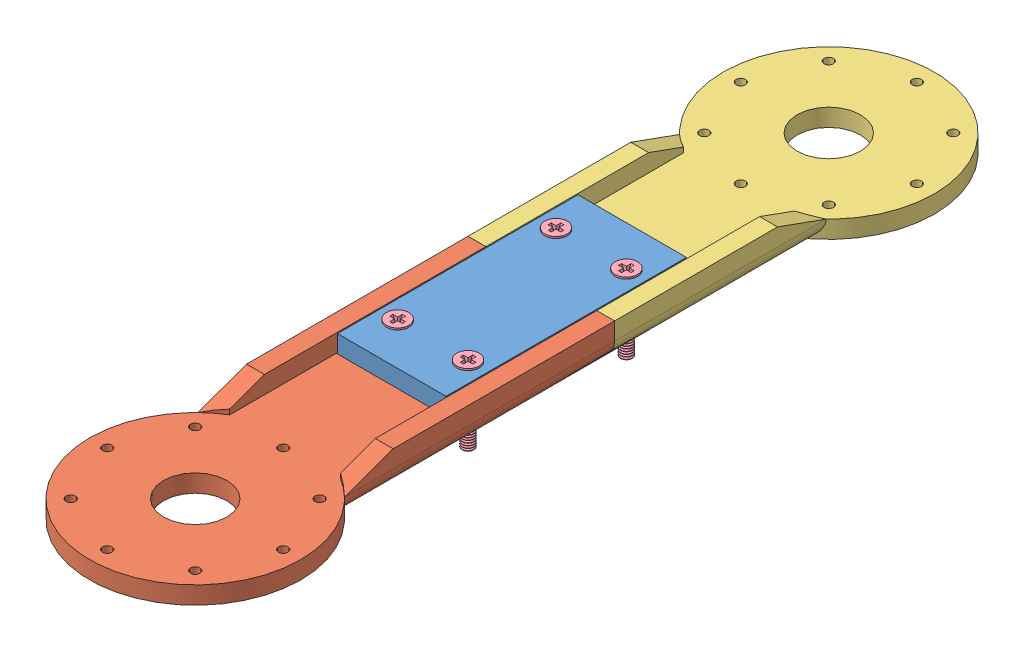
SolidWorks assembly Ensamblaje-Eslabon2AB, configuration Predeterminado. Lengths in mm.
Overall size (35.99 13 144).
7 component instances, 4 part files, 14 mates.
Components (placement in the parent):
- Agarre-Eslabon2AyB-1: Agarre-Eslabon2AyB [Predeterminado] at (-14.421 1.0451 41) size (18.5 3 41)
- Eslabon2A-1: Eslabon2A [Predeterminado] at (-11.6524 -1.9549 75.4017) x (1 0 0) z (0 0 1) size (35.99 6 77)
- Eslabon2B-1: Eslabon2B [Predeterminado] at (-11.1985 -1.9549 7.7213) x (-1 0 0) z (0 0 -1) size (35.99 6 77)
- flat head screw_am-2: flat head screw_am [B18.6.7M - M2 x 0.4 x 13 Type I Cross Recessed FHMS --13S] at (-5.4254 4.3451 55.0617) x (0 -1 0) z (0.013375 0 0.999911) size (13 3.8 3.8)
- flat head screw_am-3: flat head screw_am [B18.6.7M - M2 x 0.4 x 13 Type I Cross Recessed FHMS --13S] at (-17.425 4.3451 55.0617) x (0 -1 0) z (0 0 1) size (13 3.8 3.8)
- flat head screw_am-4: flat head screw_am [B18.6.7M - M2 x 0.4 x 13 Type I Cross Recessed FHMS --13S] at (-17.4254 4.3451 28.0617) x (0 -1 0) z (0 0 1) size (13 3.8 3.8)
- flat head screw_am-5: flat head screw_am [B18.6.7M - M2 x 0.4 x 13 Type I Cross Recessed FHMS --13S] at (-5.4254 4.3451 28.0617) x (0 -1 0) z (0 0 1) size (13 3.8 3.8)
Mates (geometry in assembly coordinates):
- Coincidente2: coincident: plane of Eslabon2A-1 through (1.0746 1.0451 36.5614) normal (1 0 0); plane of Eslabon2B-1 through (1.0746 1.0451 36.5614) normal (1 0 0)
- Coincidente3: coincident: plane of Eslabon2A-1 through (-18.9254 1.0451 46.5614) normal (0 0 -1); plane of Eslabon2B-1 through (-3.9254 1.0451 46.5614) normal (0 0 1)
- Coincidente4: coincident: plane of Eslabon2A-1 through (-11.4254 1.0451 95.565) normal (0 1 0); plane of Eslabon2B-1 through (-11.4254 1.0451 -12.4419) normal (0 1 0)
- Coincidente5: coincident: plane of Agarre-Eslabon2AyB-1 through (-14.421 1.0451 41) normal (0 -1 0); plane of Eslabon2A-1 through (-11.4254 1.0451 95.565) normal (0 1 0)
- Concéntrica1: concentric: cylinder of Agarre-Eslabon2AyB-1 through (-5.4254 4.0451 55.0617) axis (0 -1 0) radius 1; cylinder of Eslabon2A-1 through (-5.4254 1.0451 55.0614) axis (0 -1 0) radius 1
- Concéntrica2: concentric: cylinder of Agarre-Eslabon2AyB-1 through (-5.4254 4.0451 28.0617) axis (0 -1 0) radius 1; cylinder of Eslabon2B-1 through (-5.4254 1.0451 28.0617) axis (0 -1 0) radius 1
- Concéntrica3: concentric: cylinder of Agarre-Eslabon2AyB-1 through (-5.4254 4.0451 55.0617) axis (0 -1 0) radius 1; cone of flat head screw_am-2 through (-5.4254 4.0451 55.0617) axis (0 -1 0)
- Concéntrica4: concentric: cylinder of Agarre-Eslabon2AyB-1 through (-17.425 4.0451 55.0617) axis (0 -1 0) radius 0.9998; cone of flat head screw_am-3 through (-17.425 4.0451 55.0617) axis (0 -1 0)
- Concéntrica5: concentric: cylinder of Agarre-Eslabon2AyB-1 through (-17.4254 4.0451 28.0617) axis (0 -1 0) radius 1; cone of flat head screw_am-4 through (-17.4254 4.0451 28.0617) axis (0 -1 0)
- Concéntrica6: concentric: cylinder of Agarre-Eslabon2AyB-1 through (-5.4254 4.0451 28.0617) axis (0 -1 0) radius 1; cone of flat head screw_am-5 through (-5.4254 4.0451 28.0617) axis (0 -1 0)
- Coincidente6: coincident: plane of flat head screw_am-4 through (-17.4254 4.3451 28.0617) normal (0 1 0); plane of flat head screw_am-5 through (-5.4254 4.3451 28.0617) normal (0 1 0)
- Coincidente7: coincident: circle of flat head screw_am-2; plane of flat head screw_am-5 through (-5.4254 4.3451 28.0617) normal (0 1 0)
- Coincidente8: coincident: plane of flat head screw_am-2 through (-5.4254 4.3451 55.0617) normal (0 1 0); plane of flat head screw_am-3 through (-17.425 4.3451 55.0617) normal (0 1 0)
- Coincidente9: coincident: plane of Agarre-Eslabon2AyB-1 through (-14.421 4.0451 41) normal (0 1 0); circle of flat head screw_am-2
